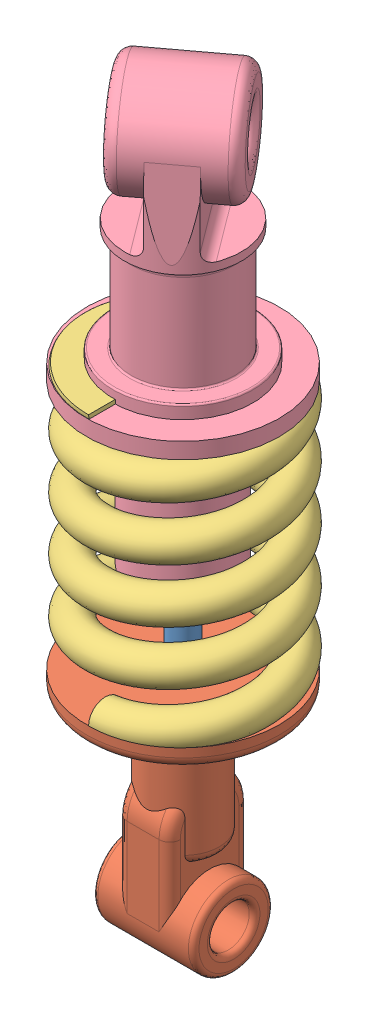
SolidWorks assembly Shock AssemblyMotion, configuration Default. Lengths in mm.
Overall size (64.38 181.99 64.38).
4 component instances, 4 part files, 6 mates.
Components (placement in the parent):
- Shock Absorber Rod_11-1: Shock Absorber Rod_11 [Default] at (4.2905 -35.2864 19.5175) x (0.958984 0 0.283461) z (-0.283461 0 0.958984) size (6.35 19.21 6.35)
- Shock Anchor_11-1: Shock Anchor_11 [Default] at (4.2905 -82.9114 19.5175) x (1 0 0) z (0 0 -1) size (46 57.15 46)
- Shock Spring_11-1: Shock Spring_11 [Default] at (4.7772 -35.2864 19.53) size (46 72.22 47.49)
- Shock Tube 1_11-1: Shock Tube 1_11 [Default] at (4.2905 57.8055 19.5175) x (0.801232 0 -0.598354) z (0.598354 0 0.801232) size (46 110.41 46)
Mates (geometry in assembly coordinates):
- Concentric1: concentric anti-aligned: circle of Shock Absorber Rod_11-1; circle of Shock Anchor_11-1
- Coincident1: coincident anti-aligned: plane of Shock Absorber Rod_11-1 through (4.2905 -35.2864 19.5175) normal (0 -1 0); plane of Shock Anchor_11-1 through (4.2905 -35.2864 19.5175) normal (0 1 0)
- Concentric2: concentric aligned: cylinder of Shock Absorber Rod_11-1 through (4.2905 -16.0724 19.5175) axis (0 -1 0) radius 3.175; cylinder of Shock Tube 1_11-1 through (4.2905 4.5429 19.5175) axis (0 -1 0) radius 3.175
- Coincident2: coincident anti-aligned: plane of Shock Anchor_11-1 through (4.2905 -35.2864 19.5175) normal (0 1 0); plane of Shock Spring_11-1 through (4.7772 -35.2864 19.53) normal (0 -1 0)
- Lock1: lock: unknown of Shock Anchor_11-1; unknown of Shock Spring_11-1
- LimitDistance5: limit distance = 59.4369 mm anti-aligned: plane of Shock Tube 1_11-1 through (4.2905 24.1505 19.5175) normal (0 -1 0); plane of Shock Anchor_11-1 through (4.2905 -35.2864 19.5175) normal (0 1 0)
